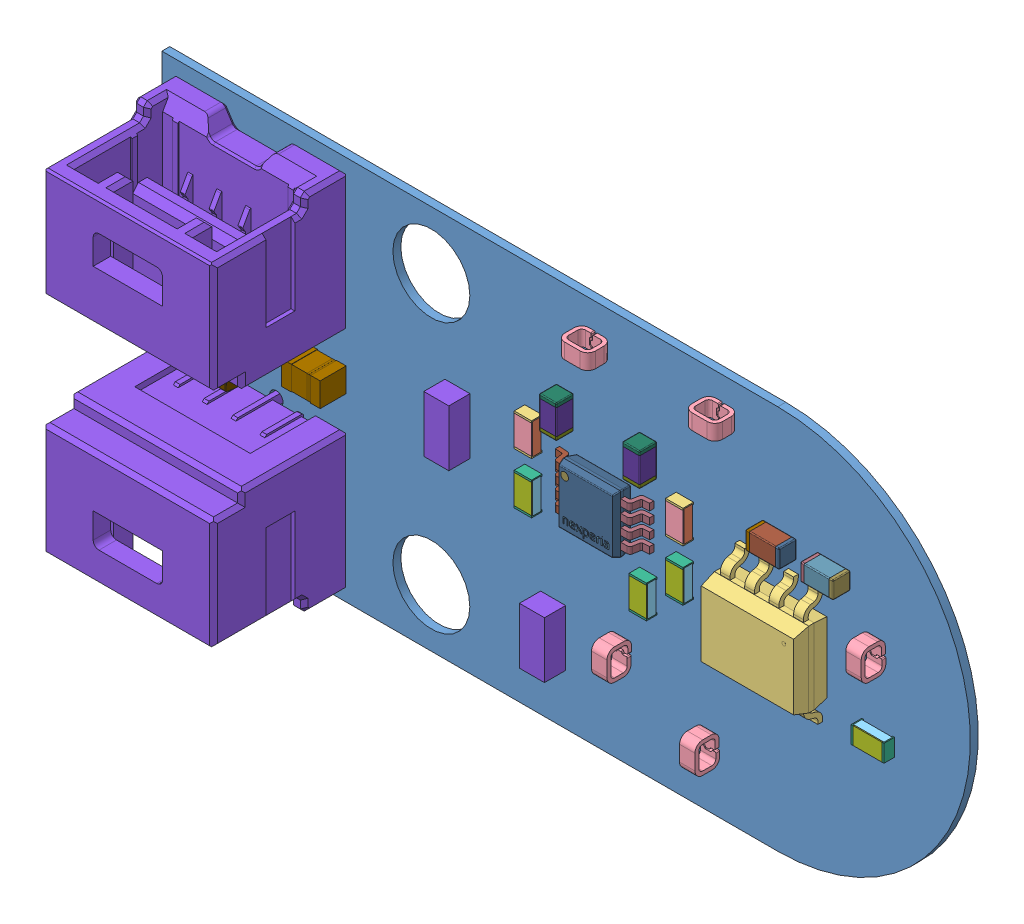
SolidWorks assembly Encoder_Board_rev1, configuration Default. Lengths in mm.
Overall size (42 20 10.35).
127 component instances, 32 part files, 0 mates.
Components (placement in the parent):
- Board-1: Board [Default] at origin size (42 20 0.41)
  - Open CASCADE STEP translator 7.5 1.1.1-1: Open CASCADE STEP translator 7.5 1.1.1 [Default] at (0 0 -0.4115) size (42 20 0.41)
- R10-1: R10 [Default] at origin size (0.9 1.7 0.55)
  - 6019289040-1: 6019289040 [Default] at (27.1699 2.6671 0) x (0 1 0) z (0 0 1) size (1.7 0.9 0.55)
    - Mid_Body-1: Mid_Body [Default] at (-0.85 -0.45 0) size (1.59 0.9 0.44)
    - Terminal-1: Terminal [Default] at (-0.85 -0.45 0) size (0.1 0.9 0.55)
      - Open CASCADE STEP translator 6.8 15.2.1-1: Open CASCADE STEP translator 6.8 15.2.1 [Default] at origin size (0.1 0.9 0.55)
    - Terminal-2: Terminal [Default] at (0.85 0.45 0) x (-1 0 0) z (0 0 1) size (0.1 0.9 0.55)
      - Open CASCADE STEP translator 6.8 15.2.1-1: Open CASCADE STEP translator 6.8 15.2.1 [Default] at origin size (0.1 0.9 0.55)
    - Mark-1: Mark [Default] at (-0.75 -0.45 0.495) size (1.5 0.9 0.06)
- R9-1: R9 [Default] at origin size (0.9 1.7 0.55)
  - 6019289920-1: 6019289920 [Default] at (27.1701 -0.0001 0) x (0 -1 0) z (0 0 1) size (1.7 0.9 0.55)
    - Mid_Body_2-1: Mid_Body_2 [Default] at (-0.85 -0.45 0) size (1.59 0.9 0.44)
    - Terminal_2-1: Terminal_2 [Default] at (-0.85 -0.45 0) size (0.1 0.9 0.55)
      - Open CASCADE STEP translator 6.8 15.2.1_2-1: Open CASCADE STEP translator 6.8 15.2.1_2 [Default] at origin size (0.1 0.9 0.55)
    - Terminal_2-2: Terminal_2 [Default] at (0.85 0.45 0) x (-1 0 0) z (0 0 1) size (0.1 0.9 0.55)
      - Open CASCADE STEP translator 6.8 15.2.1_2-1: Open CASCADE STEP translator 6.8 15.2.1_2 [Default] at origin size (0.1 0.9 0.55)
    - Mark_2-1: Mark_2 [Default] at (-0.75 -0.45 0.495) size (1.5 0.9 0.06)
- R5-1: R5 [Default] at origin size (0.9 1.7 0.55)
  - 6019289920-1: 6019289920 [Default] at (19.3041 -0.0001 0) x (0 -1 0) z (0 0 1) size (1.7 0.9 0.55)
    - Mid_Body_2-1: Mid_Body_2 [Default] at (-0.85 -0.45 0) size (1.59 0.9 0.44)
    - Terminal_2-1: Terminal_2 [Default] at (-0.85 -0.45 0) size (0.1 0.9 0.55)
      - Open CASCADE STEP translator 6.8 15.2.1_2-1: Open CASCADE STEP translator 6.8 15.2.1_2 [Default] at origin size (0.1 0.9 0.55)
    - Terminal_2-2: Terminal_2 [Default] at (0.85 0.45 0) x (-1 0 0) z (0 0 1) size (0.1 0.9 0.55)
      - Open CASCADE STEP translator 6.8 15.2.1_2-1: Open CASCADE STEP translator 6.8 15.2.1_2 [Default] at origin size (0.1 0.9 0.55)
    - Mark_2-1: Mark_2 [Default] at (-0.75 -0.45 0.495) size (1.5 0.9 0.06)
- R4-1: R4 [Default] at origin size (0.9 1.7 0.55)
  - 6019289040-1: 6019289040 [Default] at (19.3039 2.6671 0) x (0 1 0) z (0 0 1) size (1.7 0.9 0.55)
    - Mid_Body-1: Mid_Body [Default] at (-0.85 -0.45 0) size (1.59 0.9 0.44)
    - Terminal-1: Terminal [Default] at (-0.85 -0.45 0) size (0.1 0.9 0.55)
      - Open CASCADE STEP translator 6.8 15.2.1-1: Open CASCADE STEP translator 6.8 15.2.1 [Default] at origin size (0.1 0.9 0.55)
    - Terminal-2: Terminal [Default] at (0.85 0.45 0) x (-1 0 0) z (0 0 1) size (0.1 0.9 0.55)
      - Open CASCADE STEP translator 6.8 15.2.1-1: Open CASCADE STEP translator 6.8 15.2.1 [Default] at origin size (0.1 0.9 0.55)
    - Mark-1: Mark [Default] at (-0.75 -0.45 0.495) size (1.5 0.9 0.06)
- D2-1: D2 [Default] at origin size (1.3 2.92 1.1)
  - 6151663024-1: 6151663024 [Default] at (20.336 -5.903 0.01) size (1.3 2.92 1.1)
    - Extruded-1: Extruded [Default] at origin size (1.3 2.92 1.1)
- C3-1: C3 [Default] at origin size (2 1.25 1.35)
  - 6032918704-1: 6032918704 [Default] at (8.5732 0 0) x (-1 0 0) z (0 0 1) size (2 1.25 1.35)
- U2-1: U2 [Default] at origin size (4.9 3 1.12)
  - IC_NXP_Semiconductors_PCA9517DP_118_eec-1: IC_NXP_Semiconductors_PCA9517DP_118_eec [Default] at (23.106 1.397 0) size (4.9 3 1.12)
    - IC_BODY-1: IC_BODY [Default] at (0 0 0.15) x (0 -1 0) z (0 0 1) size (3 3 0.97)
    - IC_LEG-1: IC_LEG [Default] at (-2.45 1.1495 0) x (1 0 0) z (0 -1 0) size (1.05 0.77 0.35)
    - IC_LEG-2: IC_LEG [Default] at (-2.45 0.4995 0) x (1 0 0) z (0 -1 0) size (1.05 0.77 0.35)
    - IC_LEG-3: IC_LEG [Default] at (-2.45 -0.1505 0) x (1 0 0) z (0 -1 0) size (1.05 0.77 0.35)
    - IC_LEG-4: IC_LEG [Default] at (-2.45 -0.8005 0) x (1 0 0) z (0 -1 0) size (1.05 0.77 0.35)
    - circle-1: circle [Default] at (-1.0817 1.037 1.101) x (1 0 0) z (0 0 -1) size (0.4 0.4 0.01)
    - IC_LEG_MIR5-1: IC_LEG_MIR5 [Default] at (2.45 1.1495 0) x (-1 0 0) z (0 1 0) size (1.05 0.77 0.35)
    - IC_LEG_MIR5-2: IC_LEG_MIR5 [Default] at (2.45 0.4995 0) x (-1 0 0) z (0 1 0) size (1.05 0.77 0.35)
    - IC_LEG_MIR5-3: IC_LEG_MIR5 [Default] at (2.45 -0.1505 0) x (-1 0 0) z (0 1 0) size (1.05 0.77 0.35)
    - IC_LEG_MIR5-4: IC_LEG_MIR5 [Default] at (2.45 -0.8005 0) x (-1 0 0) z (0 1 0) size (1.05 0.77 0.35)
    - Nexperia-1: Nexperia [Default] at (-0.092 -0.9859 1.1) size (2.4 0.59 0.04)
- R6-1: R6 [Default] at origin size (0.9 1.7 0.55)
  - 6019289920-1: 6019289920 [Default] at (25.2731 -1.6511 0) x (0 -1 0) z (0 0 1) size (1.7 0.9 0.55)
    - Mid_Body_2-1: Mid_Body_2 [Default] at (-0.85 -0.45 0) size (1.59 0.9 0.44)
    - Terminal_2-1: Terminal_2 [Default] at (-0.85 -0.45 0) size (0.1 0.9 0.55)
      - Open CASCADE STEP translator 6.8 15.2.1_2-1: Open CASCADE STEP translator 6.8 15.2.1_2 [Default] at origin size (0.1 0.9 0.55)
    - Terminal_2-2: Terminal_2 [Default] at (0.85 0.45 0) x (-1 0 0) z (0 0 1) size (0.1 0.9 0.55)
      - Open CASCADE STEP translator 6.8 15.2.1_2-1: Open CASCADE STEP translator 6.8 15.2.1_2 [Default] at origin size (0.1 0.9 0.55)
    - Mark_2-1: Mark_2 [Default] at (-0.75 -0.45 0.495) size (1.5 0.9 0.06)
- C5-1: C5 [Default] at origin size (0.9 1.7 0.9)
  - 5943011504-1: 5943011504 [Default] at (20.947 4.445 0) x (0 -1 0) z (0 0 1) size (1.7 0.9 0.9)
    - Terminal_3-1: Terminal_3 [Default] at (-0.85 -0.45 0) size (1.7 0.9 0.9)
      - Open CASCADE STEP translator 6.8 6.1.1-1: Open CASCADE STEP translator 6.8 6.1.1 [Default] at origin size (0.2 0.9 0.9)
      - Open CASCADE STEP translator 6.8 6.1.2-1: Open CASCADE STEP translator 6.8 6.1.2 [Default] at origin size (0.2 0.9 0.9)
    - Mid_Body-1: Mid_Body [Default] at (-0.85 -0.45 0) size (1.3 0.9 0.9)
      - Open CASCADE STEP translator 6.8 6.2.1-1: Open CASCADE STEP translator 6.8 6.2.1 [Default] at origin size (1.3 0.9 0.9)
- C4-1: C4 [Default] at origin size (0.9 1.7 0.9)
  - 5943011504-1: 5943011504 [Default] at (25.265 4.445 0) x (0 -1 0) z (0 0 1) size (1.7 0.9 0.9)
    - Terminal_3-1: Terminal_3 [Default] at (-0.85 -0.45 0) size (1.7 0.9 0.9)
      - Open CASCADE STEP translator 6.8 6.1.1-1: Open CASCADE STEP translator 6.8 6.1.1 [Default] at origin size (0.2 0.9 0.9)
      - Open CASCADE STEP translator 6.8 6.1.2-1: Open CASCADE STEP translator 6.8 6.1.2 [Default] at origin size (0.2 0.9 0.9)
    - Mid_Body-1: Mid_Body [Default] at (-0.85 -0.45 0) size (1.3 0.9 0.9)
      - Open CASCADE STEP translator 6.8 6.2.1-1: Open CASCADE STEP translator 6.8 6.2.1 [Default] at origin size (1.3 0.9 0.9)
- D1-1: D1 [Default] at origin size (5.2 2.61 2.4)
  - Diode_Diodes_Inc_SMAJ5_0A-13-F_eec-1: Diode_Diodes_Inc_SMAJ5_0A-13-F_eec [Default] at (1.2604 -1.558 1.2999) x (-1 0 0) z (0 0 1) size (5.2 2.61 2.4)
    - Diodes Inc. SMAJ5.0A-13-F 1-1: Diodes Inc. SMAJ5.0A-13-F 1 [Default] at (-2.4537 -1.5741 -1.1) size (4.3 2.61 2.2)
    - Diodes Inc. SMAJ5.0A-13-F 2-1: Diodes Inc. SMAJ5.0A-13-F 2 [Default] at (-4.8275 -0.8491 -0.6375) x (1 0 0) z (0 -1 0) size (1.14 1.33 1.45)
    - Diodes Inc. SMAJ5.0A-13-F 2_MIR-1: Diodes Inc. SMAJ5.0A-13-F 2_MIR [Default] at (-0.08 -0.8491 -0.6375) x (-1 0 0) z (0 1 0) size (1.14 1.33 1.45)
- U1-1: U1 [Default] at origin size (4.91 6 1.76)
  - 6689449984-1: 6689449984 [Default] at (32.172 0 0) x (0 -1 0) z (0 0 1) size (6 4.91 1.76)
- TP5-1: TP5 [Default] at origin size (0.8 1.6 1.28)
  - Conn_Harwin_S2761-46R_eec-1: Conn_Harwin_S2761-46R_eec [Default] at (24.003 -4.953 0) x (0 1 0) z (0 0 1) size (1.6 0.8 1.28)
    - TP-1: TP [Default] at origin size (1.6 0.8 1.28)
- TP4-1: TP4 [Default] at origin size (1.6 0.8 1.28)
  - Conn_Harwin_S2761-46R_eec-1: Conn_Harwin_S2761-46R_eec [Default] at (29.21 8.382 0) x (-1 0 0) z (0 0 1) size (1.6 0.8 1.28)
    - TP-1: TP [Default] at origin size (1.6 0.8 1.28)
- TP3-1: TP3 [Default] at origin size (0.8 1.6 1.28)
  - Conn_Harwin_S2761-46R_eec-1: Conn_Harwin_S2761-46R_eec [Default] at (28.575 -6.858 0) x (0 -1 0) z (0 0 1) size (1.6 0.8 1.28)
    - TP-1: TP [Default] at origin size (1.6 0.8 1.28)
- TP2-1: TP2 [Default] at origin size (1.6 0.8 1.28)
  - Conn_Harwin_S2761-46R_eec-1: Conn_Harwin_S2761-46R_eec [Default] at (22.606 8.255 0) x (-1 0 0) z (0 0 1) size (1.6 0.8 1.28)
    - TP-1: TP [Default] at origin size (1.6 0.8 1.28)
- TP1-1: TP1 [Default] at origin size (0.8 1.6 1.28)
  - Conn_Harwin_S2761-46R_eec-1: Conn_Harwin_S2761-46R_eec [Default] at (37.211 1.651 0) x (0 -1 0) z (0 0 1) size (1.6 0.8 1.28)
    - TP-1: TP [Default] at origin size (1.6 0.8 1.28)
- R1-1: R1 [Default] at origin size (1.7 0.9 0.55)
  - 6152273536-1: 6152273536 [Default] at (37.2111 -2.2859 0) x (1 0 0) z (0 0 1) size (1.7 0.9 0.55)
    - Mid_Body_3-1: Mid_Body_3 [Default] at (-0.85 -0.45 0) size (1.59 0.9 0.44)
    - Terminal_4-1: Terminal_4 [Default] at (-0.85 -0.45 0) size (0.1 0.9 0.55)
      - Open CASCADE STEP translator 6.8 15.2.1_3-1: Open CASCADE STEP translator 6.8 15.2.1_3 [Default] at origin size (0.1 0.9 0.55)
    - Terminal_4-2: Terminal_4 [Default] at (0.85 0.45 0) x (-1 0 0) z (0 0 1) size (0.1 0.9 0.55)
      - Open CASCADE STEP translator 6.8 15.2.1_3-1: Open CASCADE STEP translator 6.8 15.2.1_3 [Default] at origin size (0.1 0.9 0.55)
    - Mark_3-1: Mark_3 [Default] at (-0.75 -0.45 0.495) size (1.5 0.9 0.06)
- J2-1: J2 [Default] at origin size (8.9 7.25 10.35)
  - 5031750400-1: 5031750400 [Default] at (5.1969 6.2699 4.3628) x (1 0 0) z (0 -1 0) size (8.9 10.35 7.25)
    - Open CASCADE STEP translator 7.5 1.20.1.1-1: Open CASCADE STEP translator 7.5 1.20.1.1 [Default] at origin size (8.9 10.35 7.25)
- J1-1: J1 [Default] at origin size (8.9 7.25 10.35)
  - 5031750400-1: 5031750400 [Default] at (5.1951 -6.2699 4.3628) x (-1 0 0) z (0 1 0) size (8.9 10.35 7.25)
    - Open CASCADE STEP translator 7.5 1.20.1.1-1: Open CASCADE STEP translator 7.5 1.20.1.1 [Default] at origin size (8.9 10.35 7.25)
- D3-1: D3 [Default] at origin size (1.3 2.92 1.1)
  - 6151663024-1: 6151663024 [Default] at (15.367 1.143 0.01) size (1.3 2.92 1.1)
    - Extruded-1: Extruded [Default] at origin size (1.3 2.92 1.1)
- C2-1: C2 [Default] at origin size (1.75 0.95 0.9)
  - 6033537424-1: 6033537424 [Default] at (32.091 4.064 0) x (1 0 0) z (0 0 1) size (1.75 0.95 0.9)
    - Terminal_5-1: Terminal_5 [Default] at (-0.875 -0.475 0) size (1.75 0.95 0.9)
      - Open CASCADE STEP translator 6.8 142.1.1-1: Open CASCADE STEP translator 6.8 142.1.1 [Default] at origin size (0.2 0.95 0.9)
      - Open CASCADE STEP translator 6.8 142.1.2-1: Open CASCADE STEP translator 6.8 142.1.2 [Default] at origin size (0.2 0.95 0.9)
    - Mid_Body_2-1: Mid_Body_2 [Default] at (-0.875 -0.475 0) size (1.35 0.95 0.9)
      - Open CASCADE STEP translator 6.8 142.2.1-1: Open CASCADE STEP translator 6.8 142.2.1 [Default] at origin size (1.35 0.95 0.9)
- C1-1: C1 [Default] at origin size (1.7 0.9 0.9)
  - 6689447584-1: 6689447584 [Default] at (34.915 4.064 0) x (-1 0 0) z (0 0 1) size (1.7 0.9 0.9)
    - Terminal_6-1: Terminal_6 [Default] at (-0.85 -0.45 0) size (1.7 0.9 0.9)
      - Open CASCADE STEP translator 6.8 6.1.1_2-1: Open CASCADE STEP translator 6.8 6.1.1_2 [Default] at origin size (0.2 0.9 0.9)
      - Open CASCADE STEP translator 6.8 6.1.2_2-1: Open CASCADE STEP translator 6.8 6.1.2_2 [Default] at origin size (0.2 0.9 0.9)
    - Mid_Body_3-1: Mid_Body_3 [Default] at (-0.85 -0.45 0) size (1.3 0.9 0.9)
      - Open CASCADE STEP translator 6.8 6.2.1_2-1: Open CASCADE STEP translator 6.8 6.2.1_2 [Default] at origin size (1.3 0.9 0.9)
